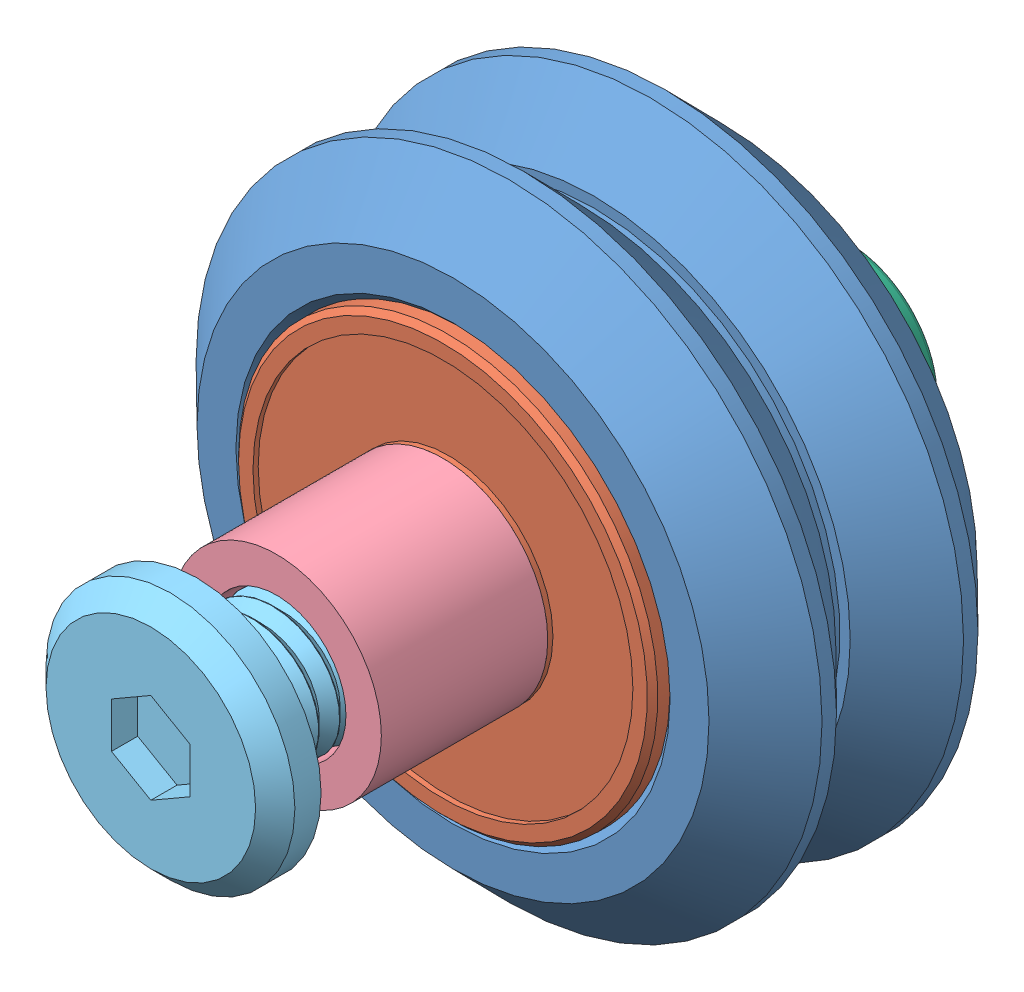
SolidWorks assembly V-Slot Delrin Dual Wheel Assembly, configuration Default. Lengths in mm.
Overall size (23.89 23.89 27.2).
7 component instances, 6 part files, 12 mates.
Components (placement in the parent):
- Delrin Dual V-Wheel-1: Delrin Dual V-Wheel [Default] at (4.1766 13.0717 -11.0846) size (23.89 23.89 10.23)
- Precision Ball Bearing-1: Precision Ball Bearing [Default] at (4.1766 13.0717 -8.0846) x (0 0 -1) z (1 0 0) size (5 16 16)
- Precision Ball Bearing-2: Precision Ball Bearing [Default] at (4.1766 13.0717 -14.0846) x (0 0 -1) z (1 0 0) size (5 16 16)
- 5mm Precision Washer-1: 5mm Precision Washer [Default] at (4.1766 13.0717 -11.5846) x (0 0 1) z (-1 0 0) size (1 10 10)
- .25 Inch Aluminum Spacer-1: .25 Inch Aluminum Spacer [Default] at (4.1766 13.0717 0.7654) x (0 0 -1) z (1 0 0) size (6.35 8 8)
- 5mm Low Profile Socket Head Screw - Multiple Lengths-1: 5mm Low Profile Socket Head Screw - Multiple Lengths [Default] at (4.1766 13.0717 5.5634) x (0 0 -1) z (1 0 0) size (27.2 9.5 9.5)
- Nylon Insert Hex Locknut 5mm-1: Nylon Insert Hex Locknut 5mm [Default] at (4.1766 13.0717 -16.5846) x (-0.923728 -0.383049 0) z (0 0 -1) size (7.68 8.82 4.5)
Mates (geometry in assembly coordinates):
- Coincident1: coincident aligned: plane of Delrin Dual V-Wheel-1 through (4.1766 21.0587 -10.5846) normal (0 0 1); plane of 5mm Precision Washer-1 through (4.1766 13.0717 -10.5846) normal (0 0 1)
- Concentric1: concentric anti-aligned: cylinder of Delrin Dual V-Wheel-1 through (4.1766 13.0717 -5.9696) axis (0 0 1) radius 6.945; cylinder of 5mm Precision Washer-1 through (4.1766 13.0717 -10.5846) axis (0 0 -1) radius 2.5
- Coincident2: coincident anti-aligned: plane of Delrin Dual V-Wheel-1 through (4.1766 21.0587 -10.5846) normal (0 0 1); plane of Precision Ball Bearing-1 through (4.1766 13.0717 -10.5846) normal (0 0 -1)
- Concentric2: concentric aligned: cylinder of Delrin Dual V-Wheel-1 through (4.1766 13.0717 -5.9696) axis (0 0 1) radius 7.987; cylinder of Precision Ball Bearing-1 through (4.1766 13.0717 -10.5846) axis (0 0 1) radius 8
- Coincident3: coincident anti-aligned: plane of Delrin Dual V-Wheel-1 through (4.1766 21.0587 -11.5846) normal (0 0 -1); plane of Precision Ball Bearing-2 through (4.1766 13.0717 -11.5846) normal (0 0 1)
- Concentric3: concentric aligned: cylinder of Delrin Dual V-Wheel-1 through (4.1766 13.0717 -5.9696) axis (0 0 1) radius 7.987; cylinder of Precision Ball Bearing-2 through (4.1766 13.0717 -16.5846) axis (0 0 1) radius 8
- Coincident4: coincident anti-aligned: plane of Precision Ball Bearing-1 through (4.1766 13.0717 -5.5846) normal (0 0 1); plane of .25 Inch Aluminum Spacer-1 through (4.1766 13.0717 -5.5846) normal (0 0 -1)
- Concentric4: concentric anti-aligned: cylinder of Precision Ball Bearing-1 through (4.1766 13.0717 -5.5846) axis (0 0 -1) radius 2.5; cylinder of .25 Inch Aluminum Spacer-1 through (4.1766 13.0717 -5.5846) axis (0 0 1) radius 2.65
- Distance2: distance = 3.048 mm anti-aligned: plane of 5mm Low Profile Socket Head Screw - Multiple Lengths-1 through (4.1766 15.5717 3.8134) normal (0 0 -1); plane of .25 Inch Aluminum Spacer-1 through (4.1766 13.0717 0.7654) normal (0 0 1)
- Concentric6: concentric aligned: cylinder of .25 Inch Aluminum Spacer-1 through (4.1766 13.0717 -5.5846) axis (0 0 1) radius 4; cylinder of 5mm Low Profile Socket Head Screw - Multiple Lengths-1 through (4.1766 13.0717 5.5634) axis (0 0 1) radius 4.75
- Coincident7: coincident anti-aligned: plane of Precision Ball Bearing-2 through (4.1766 13.0717 -16.5846) normal (0 0 -1); plane of Nylon Insert Hex Locknut 5mm-1 through (4.1766 13.0717 -16.5846) normal (0 0 1)
- Concentric7: concentric anti-aligned: cylinder of 5mm Low Profile Socket Head Screw - Multiple Lengths-1 through (4.1766 13.0717 5.5634) axis (0 0 1) radius 4.75; cylinder of Nylon Insert Hex Locknut 5mm-1 through (4.1766 13.0717 -16.5846) axis (0 0 -1) radius 2.5
